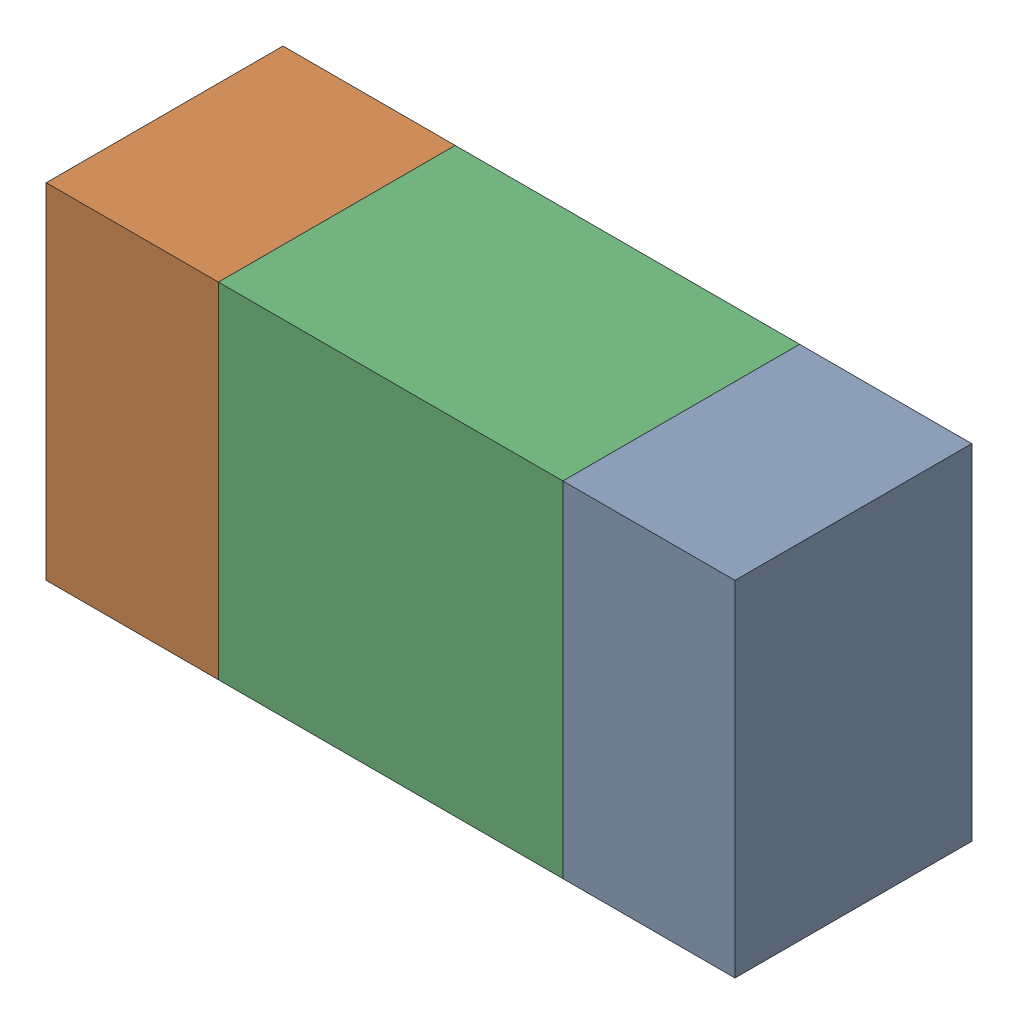
SolidWorks assembly R63, configuration ﾃﾞﾌｫﾙﾄ. Lengths in mm.
Overall size (1.6 0.8 0.55).
6 component instances, 2 part files, 0 mates.
Components (placement in the parent):
- 689261512-1: 689261512 [ﾃﾞﾌｫﾙﾄ] at (44.7999 27.7999 0) size (0.4 0.8 0.55)
  - Extruded_32-1: Extruded_32 [ﾃﾞﾌｫﾙﾄ] at origin size (0.4 0.8 0.55)
- 689261512-2: 689261512 [ﾃﾞﾌｫﾙﾄ] at (43.5999 27.7999 0) size (0.4 0.8 0.55)
  - Extruded_32-1: Extruded_32 [ﾃﾞﾌｫﾙﾄ] at origin size (0.4 0.8 0.55)
- 689261648-1: 689261648 [ﾃﾞﾌｫﾙﾄ] at (44.2 27.7999 0) size (0.8 0.8 0.55)
  - Extruded_33-1: Extruded_33 [ﾃﾞﾌｫﾙﾄ] at origin size (0.8 0.8 0.55)
